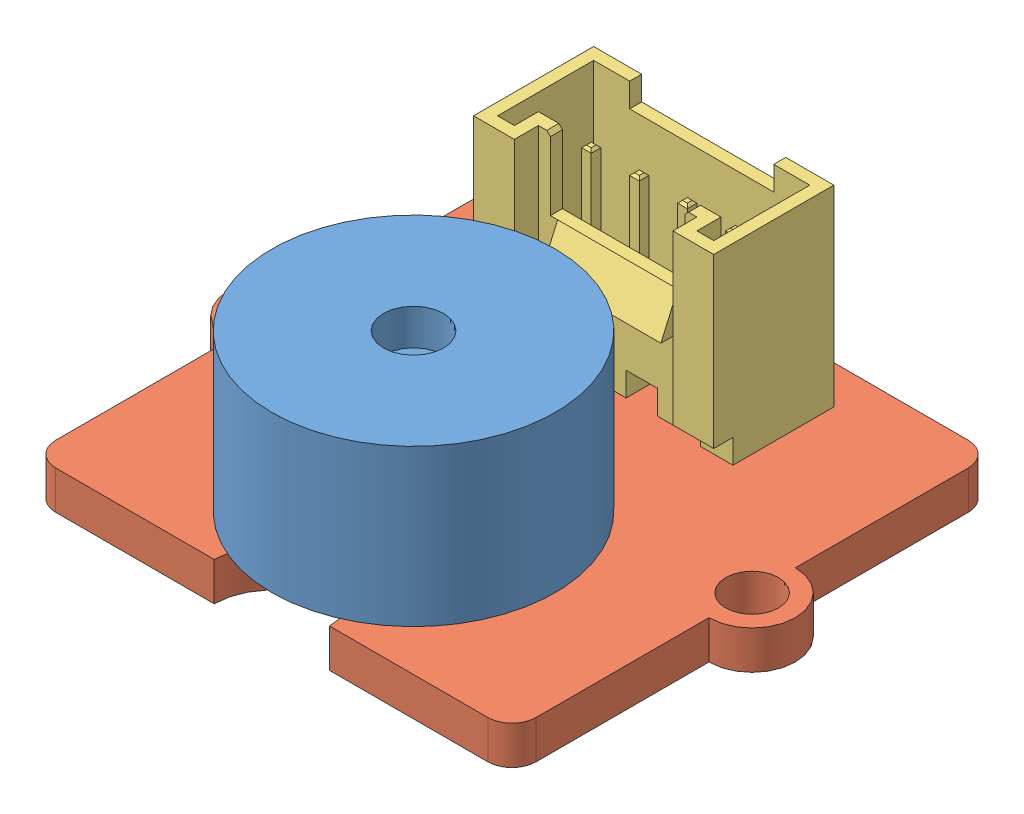
SolidWorks assembly Grove buzzer, configuration Défaut. Lengths in mm.
Overall size (23.6 11 20).
5 component instances, 5 part files, 9 mates.
Components (placement in the parent):
- buzzer-1: buzzer [Défaut] at origin size (11.8 9.5 11.8)
- PCB grove 20x20-1: PCB grove 20x20 [Défaut] at (0 -1.6 -4.1) x (0 0 1) z (-1 0 0) size (20 1.6 23.6)
- Connecteur Grove (droit)-1: Connecteur Grove (droit) [Défaut] at (0 0 -7.5) size (10 11 5)
- ssot3-1: ssot3 [Default] at (-7.3406 0 -6.1306) x (0 0 1) z (-1 0 0) size (3 1.13 3.09)
- 603 resistor 102-1: 603 resistor 102 [Default] at (-7.3848 0 -8.7435) size (2.36 0.62 1.03)
Mates (geometry in assembly coordinates):
- Verrouiller1: lock: unknown of buzzer-1; unknown of PCB grove 20x20-1
- Coïncidente3: coincident anti-aligned: plane of PCB grove 20x20-1 through (0 0 -4.1) normal (0 1 0); line of Connecteur Grove (droit)-1 through (-1.65 0 -8.5) axis (0 0 -1)
- Distance2: distance = 1.6 mm aligned: plane of PCB grove 20x20-1 through (0 0 -14.1) normal (0 0 -1); plane of Connecteur Grove (droit)-1 through (-5 8 -12.5) normal (0 0 -1)
- Distance3: distance = 5 mm aligned: plane of Connecteur Grove (droit)-1 through (5 8 -12.5) normal (1 0 0); plane of PCB grove 20x20-1 through (10 0 -4.1) normal (1 0 0)
- Coïncidente6: coincident aligned: plane of ssot3-1 through (-7.3406 0 -6.1306) normal (0 -1 0); plane of 603 resistor 102-1 through (-7.3848 0 -8.7435) normal (0 -1 0)
- Coïncidente7: coincident anti-aligned: plane of PCB grove 20x20-1 through (0 0 -4.1) normal (0 1 0); plane of ssot3-1 through (-7.3406 0 -6.1306) normal (0 -1 0)
- Distance5: distance = 2 mm: line of ssot3-1 through (-8.01 0.2 -4.6612) axis (0 0 -1); line of PCB grove 20x20-1 through (-10 0 -13.1) axis (0 0 1)
- Distance6: distance = 6.5 mm: plane of PCB grove 20x20-1 through (0 0 -14.1) normal (0 0 -1); moEndPointRef_w of ssot3-1
- Verrouiller2: lock: unknown of PCB grove 20x20-1; unknown of 603 resistor 102-1
